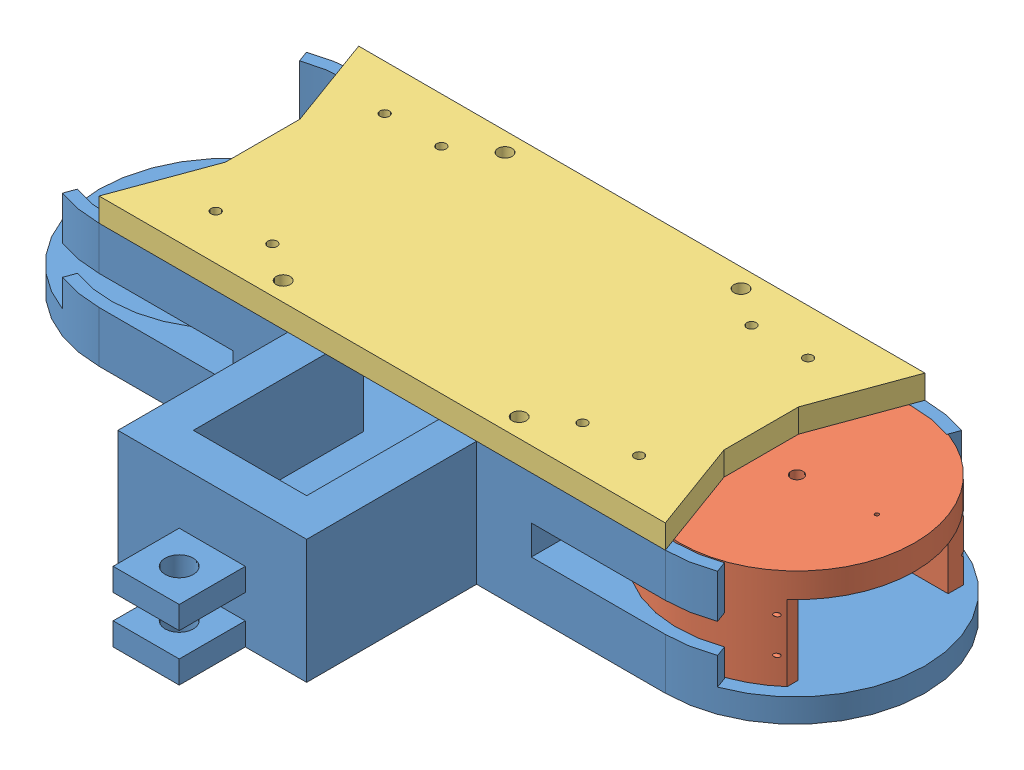
SolidWorks assembly test assem, configuration Default. Lengths in mm.
Overall size (222.2 39.69 133.35).
3 component instances, 3 part files, 4 mates.
Components (placement in the parent):
- static and shortened hipjoint-1: static and shortened hipjoint [Default] at (36.8308 83.2986 185.3552) size (222.2 33.34 133.35)
- servo hip mount v2-1: servo hip mount v2 [Default] at (126.8111 110.2861 171.3134) x (0 -1 0) z (0 0 1) size (26.99 63.37 63.37)
- servo mount plate hips V3 for battery-1: servo mount plate hips V3 for battery [Default] at (88.8083 110.2861 239.3633) size (211.67 6.35 157.02)
Mates (geometry in assembly coordinates):
- Coincident1: coincident anti-aligned: plane of static and shortened hipjoint-1 through (64.1183 83.2986 185.3552) normal (0 1 0); plane of servo hip mount v2-1 through (126.8111 83.2986 171.3134) normal (0 -1 0)
- Coincident2: coincident: plane of static and shortened hipjoint-1 through (36.8308 110.2861 136.7307) normal (0 0 -1); plane of servo mount plate hips V2 for battery-1 through (50.4746 116.6361 136.7307) normal (0 0 -1)
- Coincident3: coincident: line of static and shortened hipjoint-1 through (126.6496 110.2861 136.7307) axis (0 -1 0); line of servo mount plate hips V2 for battery-1 through (126.6496 110.2861 136.7307) axis (0 1 0)
- Coincident4: coincident anti-aligned: plane of static and shortened hipjoint-1 through (36.8308 110.2861 185.3552) normal (0 1 0); plane of servo mount plate hips V2 for battery-1 through (88.8083 110.2861 239.3633) normal (0 -1 0)
